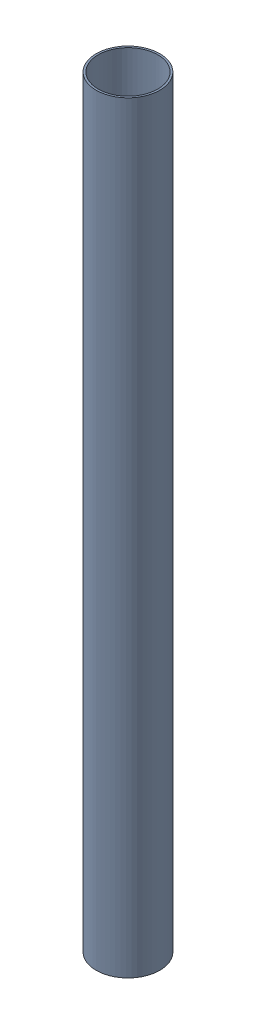
SolidWorks assembly 3-packing-canister, configuration Default. Lengths in mm.
Overall size (101.6 1219.2 101.6).
17 component instances, 2 part files, 19 mates.
Components (placement in the parent):
- payload_container-1: payload_container [Default] at origin size (101.6 1219.2 101.6)
- 3-packing-disk-1: 3-packing-disk [Default] at (0 21.336 0) x (0 0 -1) z (1 0 0) size (90.96 42.67 84.49)
  - golf ball-1: golf ball [Default] at (-24.1418 0 13.9383) size (42.67 42.67 42.67)
  - golf ball-2: golf ball [Default] at (0 0 -27.8765) size (42.67 42.67 42.67)
  - golf ball-3: golf ball [Default] at (24.1418 0 13.9383) size (42.67 42.67 42.67)
- 3-packing-disk-2: 3-packing-disk [Default] at (0 54.356 0) x (0 0 1) z (-1 0 0) size (90.96 42.67 84.49)
  - golf ball-1: golf ball [Default] at (-24.1418 0 13.9383) size (42.67 42.67 42.67)
  - golf ball-2: golf ball [Default] at (0 0 -27.8765) size (42.67 42.67 42.67)
  - golf ball-3: golf ball [Default] at (24.1418 0 13.9383) size (42.67 42.67 42.67)
- 3-packing-disk-3: 3-packing-disk [Default] at (0 87.376 0) x (0 0 1) z (1 0 0) size (90.96 42.67 84.49)
  - golf ball-1: golf ball [Default] at (-24.1418 0 13.9383) size (42.67 42.67 42.67)
  - golf ball-2: golf ball [Default] at (0 0 -27.8765) size (42.67 42.67 42.67)
  - golf ball-3: golf ball [Default] at (24.1418 0 13.9383) size (42.67 42.67 42.67)
- 3-packing-disk-4: 3-packing-disk [Default] at (0 120.396 0) x (0 0 1) z (-1 0 0) size (90.96 42.67 84.49)
  - golf ball-1: golf ball [Default] at (-24.1418 0 13.9383) size (42.67 42.67 42.67)
  - golf ball-2: golf ball [Default] at (0 0 -27.8765) size (42.67 42.67 42.67)
  - golf ball-3: golf ball [Default] at (24.1418 0 13.9383) size (42.67 42.67 42.67)
Mates (geometry in assembly coordinates):
- Tangent1: tangent anti-aligned: plane of payload_container-1 through (0 0 0) normal (0 1 0); sphere of golf ball-1
- Tangent2: tangent anti-aligned: plane of payload_container-1 through (0 0 0) normal (0 1 0); sphere of golf ball-2
- Tangent3: tangent anti-aligned: plane of payload_container-1 through (0 0 0) normal (0 1 0); sphere of golf ball-3
- Tangent5: tangent aligned: cylinder of payload_container-1 through (0 1219.2 0) axis (0 -1 0) radius 47.625; sphere of golf ball-3
- Tangent6: tangent aligned: cylinder of payload_container-1 through (0 1219.2 0) axis (0 -1 0) radius 47.625; sphere of golf ball-1
- Tangent7: tangent aligned: cylinder of payload_container-1 through (0 1219.2 0) axis (0 -1 0) radius 47.625; sphere of golf ball-2
- Distance1: distance = 21.336 mm aligned: plane of 3-packing-1 through (0 21.336 0) normal (0 1 0); plane of payload_container-1 through (0 0 0) normal (0 1 0)
- Coincident2: coincident: point of 3-packing-disk-1; line of assembly
- Coincident5: coordinate: unknown of payload_container-1
- Coincident6: coincident aligned: plane of 3-packing-1 through (0 21.336 0) normal (1 0 0)
- Coincident7: coincident: point of 3-packing-disk-2; line of assembly
- Coincident8: coincident anti-aligned: plane of 3-packing-2 through (0 54.356 0) normal (-1 0 0)
- Distance2: distance = 33.02 mm aligned: plane of 3-packing-2 through (0 54.356 0) normal (0 1 0); plane of 3-packing-1 through (0 21.336 0) normal (0 1 0)
- Coincident10: coincident: point of 3-packing-disk-3; line of assembly
- Coincident11: coincident aligned: plane of 3-packing-3 through (0 87.376 0) normal (1 0 0)
- Distance3: distance = 33.02 mm anti-aligned: plane of 3-packing-3 through (0 87.376 0) normal (0 -1 0); plane of 3-packing-2 through (0 54.356 0) normal (0 1 0)
- Coincident13: coincident: point of 3-packing-disk-4; line of assembly
- Coincident14: coincident anti-aligned: plane of 3-packing-4 through (0 120.396 0) normal (-1 0 0)
- Distance4: distance = 33.02 mm anti-aligned: plane of 3-packing-4 through (0 120.396 0) normal (0 1 0); plane of 3-packing-3 through (0 87.376 0) normal (0 -1 0)
